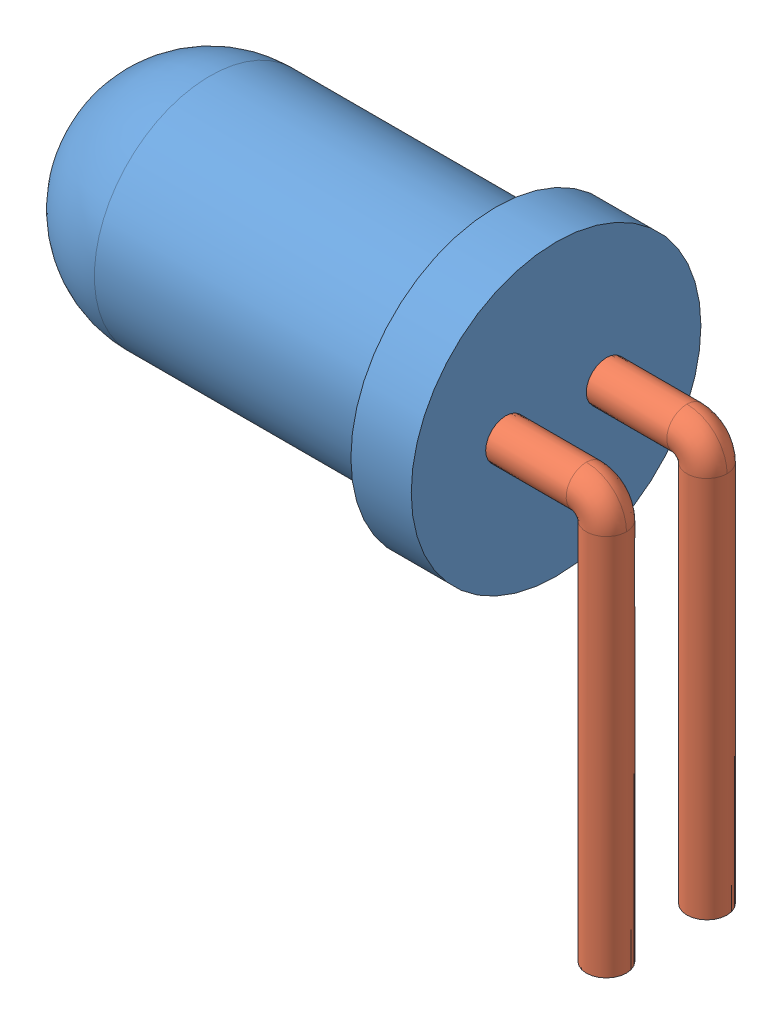
SolidWorks assembly White LED, configuration Default. Lengths in mm.
Overall size (7.36 6.92 3.66).
3 component instances, 2 part files, 6 mates.
Components (placement in the parent):
- purple LED-1: purple LED [Default] at (34.3453 0.8052 12.8117) size (5.83 3.66 3.66)
- led lead-1: led lead [Default] at (-0.1543 0.7979 1.7074) x (0 1 0) z (-1 0 0) size (5.34 0.52 1.53)
- led lead-2: led lead [Default] at (-0.1543 0.7979 0.4374) x (0 1 0) z (-1 0 0) size (5.34 0.52 1.53)
Mates (geometry in assembly coordinates):
- Coincident1: coincident aligned: plane of ? through (1.7012 0.5408 1.9645) normal (-1 0 0); plane of ? through (1.7012 0.5408 0.6945) normal (-1 0 0)
- Parallel1: parallel anti-aligned: unknown of ?
- Parallel2: parallel anti-aligned: unknown of ?
- Concentric1: concentric anti-aligned: cylinder of purple LED-1; cylinder of ?
- Concentric2: concentric anti-aligned: cylinder of purple LED-1; cylinder of ?
- Coincident2: coincident anti-aligned: plane of purple LED-1 through (-0.1543 -1.0455 2.9232) normal (1 0 0); plane of ? through (1.7012 0.5408 1.9645) normal (-1 0 0)
